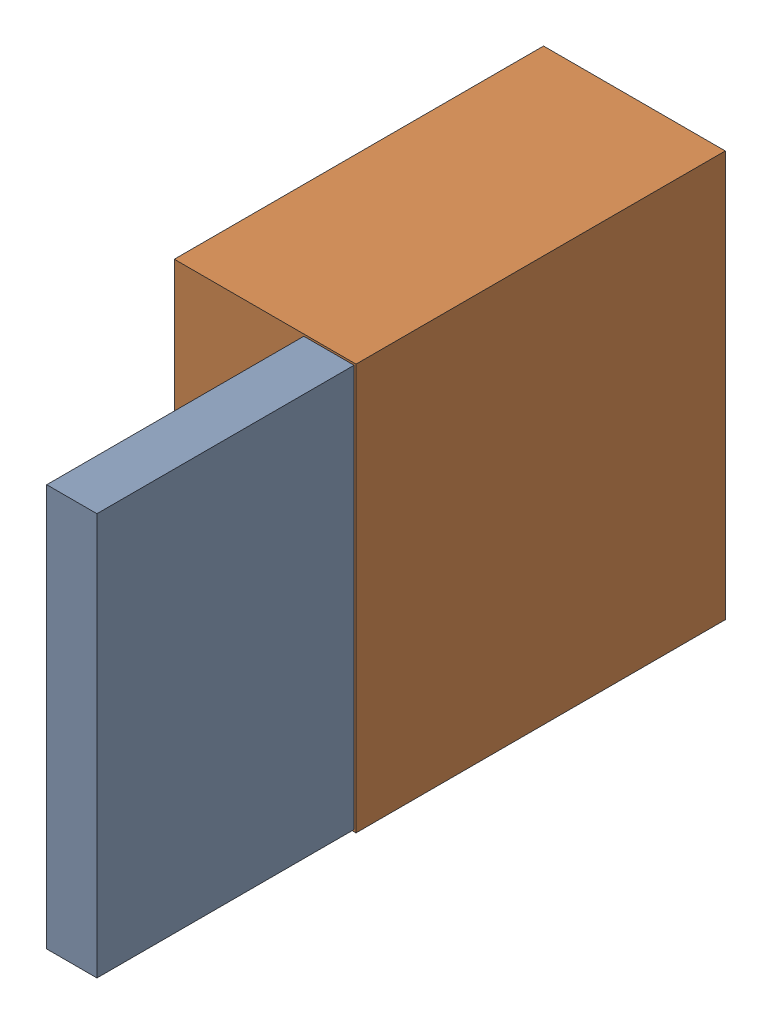
SolidWorks assembly U1, configuration Default. Lengths in mm.
Overall size (4.7 10.5 16.2).
4 component instances, 2 part files, 0 mates.
Components (placement in the parent):
- -1733502736-1: -1733502736 [Default] at (498.2 306.46 13.05) size (1.3 10.4 6.65)
  - Extruded_3-1: Extruded_3 [Default] at origin size (1.3 10.4 6.65)
- -1733506176-1: -1733506176 [Default] at (496.55 306.46 3.5) size (4.7 10.5 9.55)
  - Extruded_4-1: Extruded_4 [Default] at origin size (4.7 10.5 9.55)
